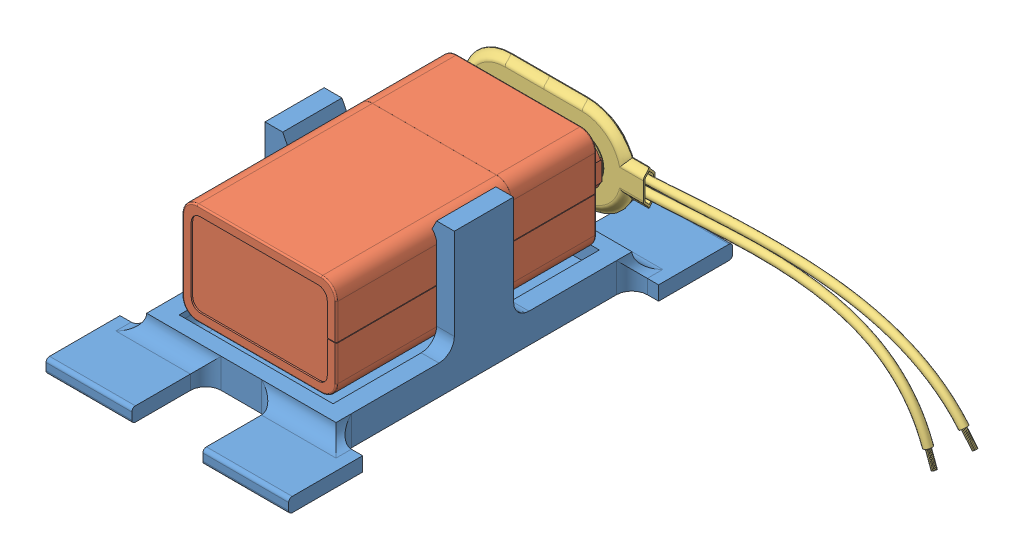
SolidWorks assembly 9V_battery_with_case, configuration Default. Lengths in mm.
Overall size (91.39 26.76 75).
3 component instances, 3 part files, 6 mates.
Components (placement in the parent):
- 9-Volt-Block Batteriehalter-Klipp-1: 9-Volt-Block Batteriehalter-Klipp [Standard] at (51.9583 32.4123 34.0334) size (41 23 75)
- 9V-battery-1: 9V-battery [ﾃﾞﾌｫﾙﾄ] at (72.0592 54.5573 -33.1978) x (1 0 0) z (0 -1 0) size (26.04 47.88 17.15)
- 9V Battery Clip Connector-1: 9V Battery Clip Connector [ﾃﾞﾌｫﾙﾄ] at (51.8083 45.9848 7.7894) x (-1 0 0) z (0 1 0) size (85.54 6.4 25.34)
Mates (geometry in assembly coordinates):
- 一致2: coincident anti-aligned: plane of 9-Volt-Block Batteriehalter-Klipp-1 through (51.9583 37.4123 34.0334) normal (0 1 0); plane of 9V-battery-1 through (51.9583 37.4123 35.2624) normal (0 -1 0)
- 幅1: width aligned: plane of 9V-battery-1 through (38.9408 45.8073 35.2624) normal (-1 0 0); plane of 9V-battery-1 through (64.9758 45.8073 35.2624) normal (1 0 0); plane of 9-Volt-Block Batteriehalter-Klipp-1 through (35.9583 37.4123 59.0334) normal (-1 0 0); plane of 9-Volt-Block Batteriehalter-Klipp-1 through (67.9583 37.4123 59.0334) normal (1 0 0)
- 幅2: width anti-aligned: plane of 9V-battery-1 through (40.4648 38.1743 55.7504) normal (0 0 1); plane of 9V-battery-1 through (51.9583 45.8073 12.3164) normal (0 0 -1); plane of 9-Volt-Block Batteriehalter-Klipp-1 through (67.9583 37.4123 9.0334) normal (0 0 -1); plane of 9-Volt-Block Batteriehalter-Klipp-1 through (67.9583 37.4123 59.0334) normal (0 0 1)
- 同心円1: concentric: cylinder of 9V-battery-1 through (58.3083 45.9848 11.1734) axis (0 0 -1) radius 3.175; cylinder of 9V Battery Clip Connector-1 through (58.3083 45.9848 8.6076) axis (0 0 1) radius 3.65
- 平行2: parallel: plane of 9-Volt-Block Batteriehalter-Klipp-1 through (51.9583 37.4123 34.0334) normal (0 1 0); line of 9V Battery Clip Connector-1 through (51.8083 53.9848 4.1476) axis (-1 0 0)
- 距離1: distance = 1 mm anti-aligned: plane of 9V-battery-1 through (46.3057 49.8595 12.1894) normal (0 0 -1); plane of 9V Battery Clip Connector-1 through (43.0701 49.8173 11.1894) normal (0 0 1)
